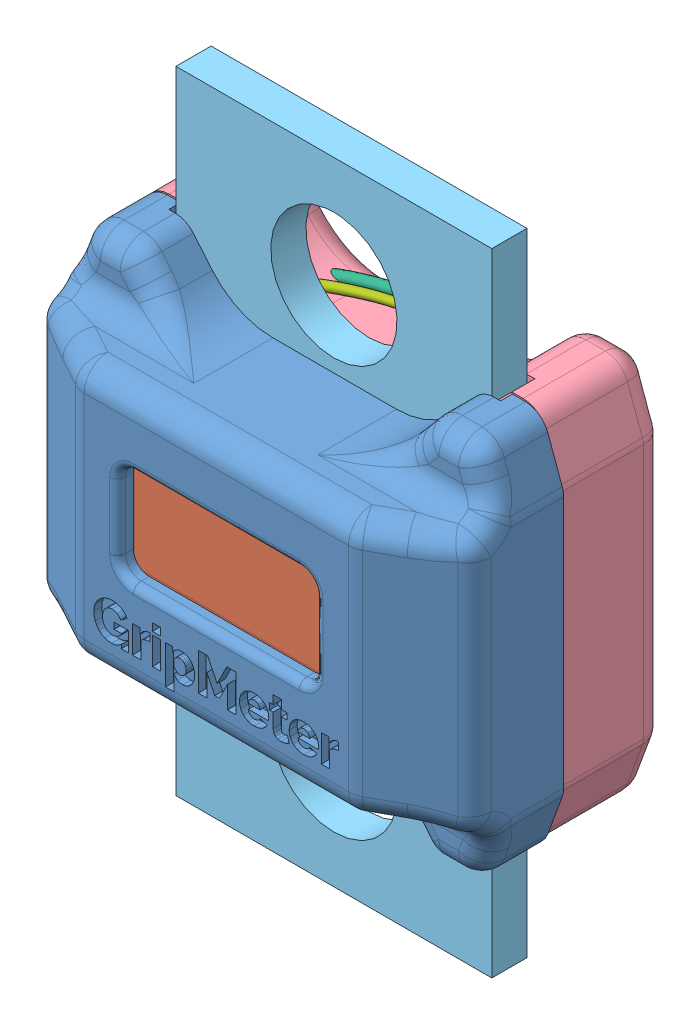
SolidWorks assembly Ensamblaje_Gripmeter_Slim_Trunks_USBC, configuration Predeterminado. Lengths in mm.
Overall size (57 80 30.33).
104 component instances, 30 part files, 12 mates.
Components (placement in the parent):
- GripMeter_Slim_Trunks_Front_USBC-1: GripMeter_Slim_Trunks_Front_USBC [Predeterminado] at (27.0701 11.0835 -92.9277) size (57 48 16.5)
- 096OLED_conv-1: 096OLED_conv [Predeterminado] at (26.9141 9.7285 -93.5479) x (1 0 0) z (0 -1 0.00002) size (26.7 3.84 22.22)
- GripMeter_PCBA-1: GripMeter_PCBA [Predeterminado] at (-97.9299 -127.6665 -98.9777) x (1 0 0) z (0 0 -1) size (53.85 25 9.71)
  - C_0805_2012Metric-1: C_0805_2012Metric [Predeterminado] at (111.61 -143.4 1.65) x (-1 0 0) z (0 0 1) size (2 1.25 1.25)
    - SOLID-1: SOLID [Predeterminado] at origin size (2 1.25 1.25)
  - C_0805_2012Metric-2: C_0805_2012Metric [Predeterminado] at (131.83 -128.25 1.65) size (2 1.25 1.25)
    - SOLID-1: SOLID [Predeterminado] at origin size (2 1.25 1.25)
  - C_0603_1608Metric-1: C_0603_1608Metric [Predeterminado] at (131.61 -126.52 1.65) size (1.6 0.8 0.8)
    - SOLID_2-1: SOLID_2 [Predeterminado] at origin size (1.6 0.8 0.8)
  - C_0805_2012Metric-3: C_0805_2012Metric [Predeterminado] at (118.81 -142.41 1.65) size (2 1.25 1.25)
    - SOLID-1: SOLID [Predeterminado] at origin size (2 1.25 1.25)
  - C_0603_1608Metric-2: C_0603_1608Metric [Predeterminado] at (122.13 -140.57 1.65) size (1.6 0.8 0.8)
    - SOLID_2-1: SOLID_2 [Predeterminado] at origin size (1.6 0.8 0.8)
  - C_0603_1608Metric-3: C_0603_1608Metric [Predeterminado] at (125.13 -140.58 1.65) size (1.6 0.8 0.8)
    - SOLID_2-1: SOLID_2 [Predeterminado] at origin size (1.6 0.8 0.8)
  - C_0805_2012Metric-4: C_0805_2012Metric [Predeterminado] at (114.38 -137.23 1.65) x (0 1 0) z (0 0 1) size (2 1.25 1.25)
    - SOLID-1: SOLID [Predeterminado] at origin size (2 1.25 1.25)
  - LED_0603_1608Metric-1: LED_0603_1608Metric [Predeterminado] at (102.26 -127.36 1.65) size (1.6 0.8 1.1)
    - SOLID_3-1: SOLID_3 [Predeterminado] at origin size (1.6 0.8 1.1)
  - D_SOD-123-1: D_SOD-123 [Predeterminado] at (108.58 -140.29 1.65) x (0 -1 0) z (0 0 1) size (3.8 1.6 1.25)
    - SOLID_4-1: SOLID_4 [Predeterminado] at origin size (3.8 1.6 1.25)
  - SOT-23-1: SOT-23 [Predeterminado] at (141.62 -141.23 1.65) size (2.5 3 1.2)
    - SOLID_5-1: SOLID_5 [Predeterminado] at origin size (2.5 3 1.2)
  - SOT-23-2: SOT-23 [Predeterminado] at (141.66 -147.65 1.65) x (0 -1 0) z (0 0 1) size (2.5 3 1.2)
    - SOLID_5-1: SOLID_5 [Predeterminado] at origin size (2.5 3 1.2)
  - SOT-23-3: SOT-23 [Predeterminado] at (111.6 -140.68 1.65) x (0 1 0) z (0 0 1) size (2.5 3 1.2)
    - SOLID_5-1: SOLID_5 [Predeterminado] at origin size (2.5 3 1.2)
  - R_0603_1608Metric-1: R_0603_1608Metric [Predeterminado] at (140.93 -144.46 1.65) x (0 -1 0) z (0 0 1) size (1.6 0.8 0.45)
    - SOLID_6-1: SOLID_6 [Predeterminado] at origin size (1.6 0.8 0.45)
  - R_0603_1608Metric-2: R_0603_1608Metric [Predeterminado] at (141.425 -138.75 1.65) x (-1 0 0) z (0 0 1) size (1.6 0.8 0.45)
    - SOLID_6-1: SOLID_6 [Predeterminado] at origin size (1.6 0.8 0.45)
  - R_0603_1608Metric-3: R_0603_1608Metric [Predeterminado] at (142.59 -144.46 1.65) x (0 -1 0) z (0 0 1) size (1.6 0.8 0.45)
    - SOLID_6-1: SOLID_6 [Predeterminado] at origin size (1.6 0.8 0.45)
  - R_0603_1608Metric-4: R_0603_1608Metric [Predeterminado] at (108.09 -125.85 1.65) size (1.6 0.8 0.45)
    - SOLID_6-1: SOLID_6 [Predeterminado] at origin size (1.6 0.8 0.45)
  - R_0603_1608Metric-5: R_0603_1608Metric [Predeterminado] at (105.42 -127.35 1.65) x (-1 0 0) z (0 0 1) size (1.6 0.8 0.45)
    - SOLID_6-1: SOLID_6 [Predeterminado] at origin size (1.6 0.8 0.45)
  - R_0603_1608Metric-6: R_0603_1608Metric [Predeterminado] at (108.98 -144.25 1.65) x (0 -1 0) z (0 0 1) size (1.6 0.8 0.45)
    - SOLID_6-1: SOLID_6 [Predeterminado] at origin size (1.6 0.8 0.45)
  - R_0603_1608Metric-7: R_0603_1608Metric [Predeterminado] at (124.3 -142.84 1.65) x (0 -1 0) z (0 0 1) size (1.6 0.8 0.45)
    - SOLID_6-1: SOLID_6 [Predeterminado] at origin size (1.6 0.8 0.45)
  - R_0603_1608Metric-8: R_0603_1608Metric [Predeterminado] at (125.86 -142.8 1.65) x (0 -1 0) z (0 0 1) size (1.6 0.8 0.45)
    - SOLID_6-1: SOLID_6 [Predeterminado] at origin size (1.6 0.8 0.45)
  - R_0603_1608Metric-9: R_0603_1608Metric [Predeterminado] at (119.075 -140.6 1.65) size (1.6 0.8 0.45)
    - SOLID_6-1: SOLID_6 [Predeterminado] at origin size (1.6 0.8 0.45)
  - R_0603_1608Metric-10: R_0603_1608Metric [Predeterminado] at (122.06 -142.08 1.65) size (1.6 0.8 0.45)
    - SOLID_6-1: SOLID_6 [Predeterminado] at origin size (1.6 0.8 0.45)
  - SOT-223-1: SOT-223 [Predeterminado] at (129.92 -133.71 1.65) x (0 -1 0) z (0 0 1) size (7 6.5 1.7)
    - SOLID_7-1: SOLID_7 [Predeterminado] at origin size (7 6.5 1.7)
  - TSOT-23-5-1: TSOT-23-5 [Predeterminado] at (109.52 -129.37 1.65) x (-1 0 0) z (0 0 1) size (2.8 2.9 0.95)
    - SOLID_8-1: SOLID_8 [Predeterminado] at origin size (2.8 2.9 0.95)
  - SOP-16_4.4x10.4mm_P1.27mm-1: SOP-16_4.4x10.4mm_P1.27mm [Predeterminado] at (120.83 -135.77 1.65) x (0 1 0) z (0 0 1) size (6.4 10.4 2.1)
    - SOLID_9-1: SOLID_9 [Predeterminado] at origin size (6.4 10.4 2.1)
  - SOIC-16_3.9x9.9mm_P1.27mm-1: SOIC-16_3.9x9.9mm_P1.27mm [Predeterminado] at (135.86 -143.9 1.65) size (6 9.9 1.75)
    - SOLID_10-1: SOLID_10 [Predeterminado] at origin size (6 9.9 1.75)
  - df13-2p-1_25ds_50_-1: df13-2p-1_25ds_50_ [Predeterminado] at (98.16 -128.54 28.65) x (0 0 1) z (-1 0 0) size (5.9 5.4 4.15)
    - COMPOUND-1: COMPOUND [Predeterminado] at origin size (5.9 5.4 4.15)
  - jst_zh_1_5mm_4d-1: jst_zh_1_5mm_4d [Predeterminado] at (118.48 -146.42 1.65) size (7.5 6 6.48)
    - COMPOUND_2-1: COMPOUND_2 [Predeterminado] at origin size (7.5 6 6.48)
  - LED_0603_1608Metric-2: LED_0603_1608Metric [Predeterminado] at (101.56 -125.84 1.65) x (-1 0 0) z (0 0 1) size (1.6 0.8 1.1)
    - SOLID_3-1: SOLID_3 [Predeterminado] at origin size (1.6 0.8 1.1)
  - SOT-23-4: SOT-23 [Predeterminado] at (115.26 -141.56 1.65) x (0 -1 0) z (0 0 1) size (2.5 3 1.2)
    - SOLID_5-1: SOLID_5 [Predeterminado] at origin size (2.5 3 1.2)
  - R_0603_1608Metric-11: R_0603_1608Metric [Predeterminado] at (104.75 -125.85 1.65) size (1.6 0.8 0.45)
    - SOLID_6-1: SOLID_6 [Predeterminado] at origin size (1.6 0.8 0.45)
  - User Library-YX7525P-1: User Library-YX7525P [Predeterminado] at (138.6 -129.83 1.65) size (7.56 7.56 2.51)
    - SOLID_11-1: SOLID_11 [Predeterminado] at origin size (7.56 7.56 2.51)
  - LED_0603_1608Metric-3: LED_0603_1608Metric [Predeterminado] at (148.09 -126.72 1.65) x (-1 0 0) z (0 0 1) size (1.6 0.8 1.1)
    - SOLID_3-1: SOLID_3 [Predeterminado] at origin size (1.6 0.8 1.1)
  - R_0603_1608Metric-12: R_0603_1608Metric [Predeterminado] at (145.09 -126.72 1.65) size (1.6 0.8 0.45)
    - SOLID_6-1: SOLID_6 [Predeterminado] at origin size (1.6 0.8 0.45)
  - User Library-SK-22D02-PG4-1: User Library-SK-22D02-PG4 [Predeterminado] at (103.2 -134.14 1.65) x (0 1 0) z (0 0 1) size (10.4 10.1 7.6)
    - COMPOUND_3-1: COMPOUND_3 [Predeterminado] at origin size (10.4 10.1 7.6)
  - C_0805_2012Metric-5: C_0805_2012Metric [Predeterminado] at (127.01 -147.52 1.65) x (0 -1 0) z (0 0 1) size (2 1.25 1.25)
    - SOLID-1: SOLID [Predeterminado] at origin size (2 1.25 1.25)
  - R_0603_1608Metric-13: R_0603_1608Metric [Predeterminado] at (129.64 -147.69 1.65) x (-1 0 0) z (0 0 1) size (1.6 0.8 0.45)
    - SOLID_6-1: SOLID_6 [Predeterminado] at origin size (1.6 0.8 0.45)
  - R_0603_1608Metric-14: R_0603_1608Metric [Predeterminado] at (129.65 -146.17 1.65) size (1.6 0.8 0.45)
    - SOLID_6-1: SOLID_6 [Predeterminado] at origin size (1.6 0.8 0.45)
  - D_SOD-123F-1: D_SOD-123F [Predeterminado] at (141.02 -136.69 1.65) size (3.5 1.6 1.1)
    - SOLID_12-1: SOLID_12 [Predeterminado] at origin size (3.5 1.6 1.1)
  - SOT-23-5: SOT-23 [Predeterminado] at (136.76 -136.63 1.65) size (2.5 3 1.2)
    - SOLID_5-1: SOLID_5 [Predeterminado] at origin size (2.5 3 1.2)
  - R_0603_1608Metric-15: R_0603_1608Metric [Predeterminado] at (134.25 -136.63 1.65) x (0 1 0) z (0 0 1) size (1.6 0.8 0.45)
    - SOLID_6-1: SOLID_6 [Predeterminado] at origin size (1.6 0.8 0.45)
  - df13-4p-1_25ds_50_-1: df13-4p-1_25ds_50_ [Predeterminado] at (105.5 -128.48 29.15) x (0 0 1) z (-1 0 0) size (5.9 5.4 6.65)
    - COMPOUND_4-1: COMPOUND_4 [Predeterminado] at origin size (5.9 5.4 6.65)
  - DX07S016JA1-V1_JAE_Proprietary-1: DX07S016JA1-V1_JAE_Proprietary [Predeterminado] at (103.97 -144.91 3.15) x (0 -1 0) z (0 0 1) size (8.94 6.9 4.06)
    - SOLID_13-1: SOLID_13 [Predeterminado] at origin size (8.94 6.9 4.06)
  - C_0603_1608Metric-4: C_0603_1608Metric [Predeterminado] at (129.65 -149.21 1.65) x (-1 0 0) z (0 0 1) size (1.6 0.8 0.8)
    - SOLID_2-1: SOLID_2 [Predeterminado] at origin size (1.6 0.8 0.8)
  - User Library-ESP321-1: User Library-ESP321 [Predeterminado] at (137.2 -137 -0.05) x (0 1 0) z (0 0 -1) size (18 25.5 2.92)
    - COMPOUND_5-1: COMPOUND_5 [Predeterminado] at origin size (18 25.5 2.92)
  - _autosave-GripMeter PCB-1: _autosave-GripMeter PCB [Predeterminado] at origin size (50 25 1.6)
- GripMeter_Slim_Trunks_Back-1: GripMeter_Slim_Trunks_Back [Predeterminado] at (26.8201 9.8335 -119.5277) size (54.5 48 15.23)
- Scale_sensor-1: Scale_sensor [Predeterminado] at (26.8201 8.5835 -106.0777) x (1 0 0) z (0 1 0) size (40 4.45 80)
- 3.3V 500Mah Battery v2-1: 3.3V 500Mah Battery v2 [Predeterminado] at (24.5701 9.3335 -112.5277) x (0 -1 0) z (1 0 0) size (34.6 6.63 38.21)
  - Black wIRE-1: Black wIRE [Predeterminado] at (-17 0.9 -20) size (7.14 2.41 17.5)
  - Red Wire-1: Red Wire [Predeterminado] at (-17 0.9 -20) size (7.13 1.93 17.65)
  - Connector-1: Connector [Predeterminado] at (-17 0.9 -20) size (4.5 5.75 6.7)
  - Body1-1: Body1 [Predeterminado] at origin size (26.21 6.21 29.1)
  - Body2-1: Body2 [Predeterminado] at origin size (26.21 6.1 9.1)
  - Text-1: Text [Predeterminado] at origin size (2.27 0.1 18.35)
  - Text (1)-1: Text (1) [Predeterminado] at origin size (0.3 0.1 0.3)
Mates (geometry in assembly coordinates):
- Coincidente1: coincident: plane of GripMeter_Slim_Trunks_Front_USBC-1 through (27.0701 11.0835 -92.9277) normal (0 0 -1); plane of 096OLED_conv-1 through (26.9141 9.7285 -92.9277) normal (0 0 1)
- Distancia2: distance = 0.5 mm: plane of GripMeter_PCBA-1/_autosave-GripMeter PCB-1 through (52.0701 -2.6665 -98.9777) normal (1 0 0); plane of GripMeter_Slim_Trunks_Front_USBC-1 through (52.5701 -2.9165 -100.4277) normal (-1 0 0)
- Distancia4: distance = 0.55 mm: plane of GripMeter_Slim_Trunks_Front_USBC-1 through (27.0701 11.0835 -98.4277) normal (0 0 -1); plane of GripMeter_PCBA-1/_autosave-GripMeter PCB-1 through (27.0701 9.8335 -98.9777) normal (0 0 1)
- Concéntrica11: concentric: cylinder of GripMeter_Slim_Trunks_Front_USBC-1 through (4.5701 26.5835 -99.4277) axis (0 0 -1) radius 1.25; cylinder of GripMeter_Slim_Trunks_Back-1 through (4.5701 26.5835 -121.0277) axis (0 0 1) radius 1.5
- Paralelo9: parallel: plane of GripMeter_Slim_Trunks_Front_USBC-1 through (53.5701 25.8045 -107.4277) normal (-1 0 0); plane of GripMeter_Slim_Trunks_Back-1 through (52.8701 -6.3138 -107.6277) normal (1 0 0)
- Distancia5: distance = 0.2 mm: plane of GripMeter_Slim_Trunks_Front_USBC-1 through (51.5701 25.8045 -107.4277) normal (0 0 -1); plane of GripMeter_Slim_Trunks_Back-1 through (4.4005 -11.1665 -107.6277) normal (0 0 1)
- Coincidente11: coincident: plane of GripMeter_Slim_Trunks_Back-1 through (4.4005 30.8335 -110.5277) normal (0 0 1); plane of Scale_sensor-1 through (6.8201 -10.1665 -110.5277) normal (0 0 -1)
- Concéntrica14: concentric: cylinder of GripMeter_Slim_Trunks_Back-1 through (46.8201 -10.1665 -106.0277) axis (0 0 -1) radius 2; cylinder of Scale_sensor-1 through (46.8201 -10.1665 -110.5277) axis (0 0 1) radius 3
- Paralelo10: parallel: plane of GripMeter_Slim_Trunks_Front_USBC-1 through (0.5701 -6.1375 -107.4277) normal (1 0 0); plane of Scale_sensor-1 through (6.8201 26.8335 -110.5277) normal (-1 0 0)
- Distancia8: distance = 3 mm: plane of GripMeter_Slim_Trunks_Front_USBC-1 through (9.5701 -6.6665 -90.9277) normal (0 -1 0); plane of 3.3V 500Mah Battery v2-1/Body1-1 through (47.0701 -3.6665 -112.5277) normal (0 -1 0)
- Distancia6: distance = 1 mm: plane of ? through (32.5701 9.3335 -118.5277) normal (0 0 -1); plane of GripMeter_Slim_Trunks_Back-1 through (4.4005 30.8335 -119.5277) normal (0 0 1)
- Distancia7: distance = 5 mm: plane of ? through (47.0701 22.3335 -112.5277) normal (1 0 0); plane of GripMeter_Slim_Trunks_Back-1 through (52.0701 22.0009 -110.5277) normal (-1 0 0)
